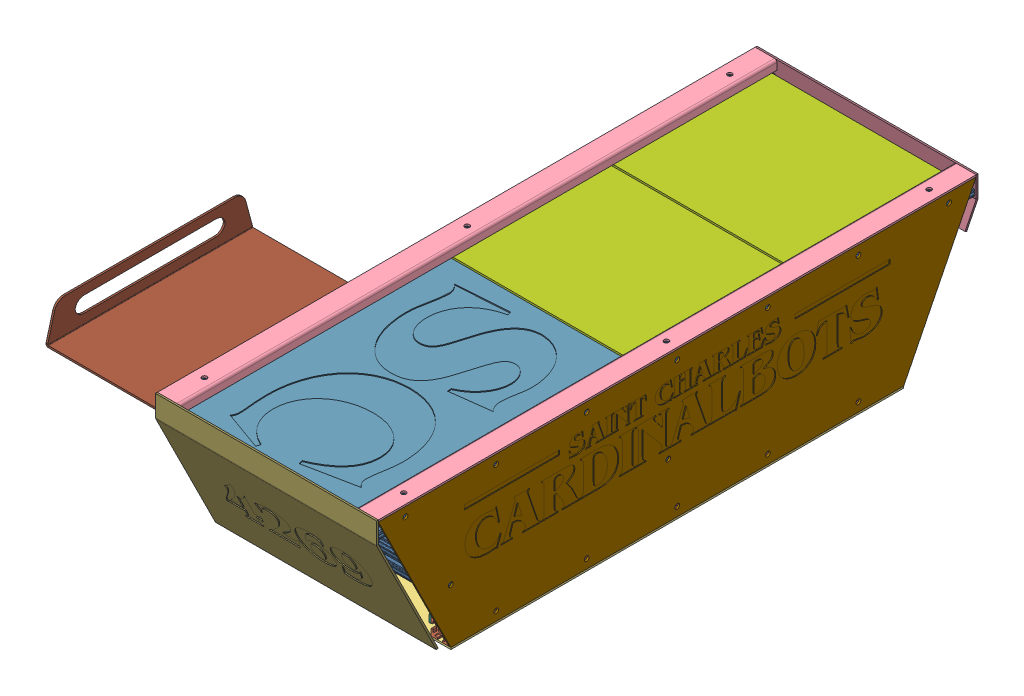
SolidWorks assembly Drive Station Assembly, configuration Default. Lengths in mm.
Overall size (576.52 208.28 843.28).
22 component instances, 14 part files, 56 mates.
Components (placement in the parent):
- Drive Station Side with T-Slot-1: Drive Station Side with T-Slot [Default] at (368.9985 440.9846 611.3533) size (25.4 203.2 838.2)
  - Modifiable T-Slot Bar (33 in)-1: Modifiable T-Slot Bar (33 in) [Default] at (22.4388 294.0274 200.7009) x (0 0 1) z (-1 0 0) size (838.2 25.4 25.4)
  - Modifiable T-Slot Bar (25 in)-1: Modifiable T-Slot Bar (25 in) [Default] at (-71.4513 116.2274 637.1834) x (0 0 -1) z (1 0 0) size (635 25.4 25.4)
- Drive station bottom plate-1: Drive station bottom plate [Default] at (484.1923 585.9717 1081.0955) x (0 0 1) z (-1 0 0) size (635 2.54 309.88)
- Drive Station Side with T-Slot-2: Drive Station Side with T-Slot [Default] at (599.3861 440.9846 1550.8376) x (-1 0 0) z (0 0 -1) size (25.4 203.2 838.2)
  - Modifiable T-Slot Bar (33 in)-1: Modifiable T-Slot Bar (33 in) [Default] at (22.4388 294.0274 200.7009) x (0 0 1) z (-1 0 0) size (838.2 25.4 25.4)
  - Modifiable T-Slot Bar (25 in)-1: Modifiable T-Slot Bar (25 in) [Default] at (-71.4513 116.2274 637.1834) x (0 0 -1) z (1 0 0) size (635 25.4 25.4)
- T-slot cover - 33-1: T-slot cover - 33 [Default] at (625.1623 791.7117 1081.0955) x (0 0 -1) z (1 0 0) size (838.2 12.7 30.48)
- T-slot cover - 33-2: T-slot cover - 33 [Default] at (343.2223 791.7117 1081.0955) x (0 0 1) z (-1 0 0) size (838.2 12.7 30.48)
- Electronics Plate-1: Electronics Plate [Default] at (483.8846 597.9732 1076.7796) x (0 0 -1) z (0 1 0) size (508 269.24 2.54)
- T-slot cover - 25-1: T-slot cover - 25 [Default] at (623.8923 613.9117 1081.0955) x (0 0 -1) z (1 0 0) size (635 12.7 27.94)
- T-slot cover - 25-2: T-slot cover - 25 [Default] at (344.4923 613.9117 1081.0955) x (0 0 1) z (-1 0 0) size (635 12.7 27.94)
- Joystick Plate-1: Joystick Plate [Default] at (485.4086 773.2332 1001.7205) x (0 0 1) z (0 -1 0) size (222.25 269.24 2.54)
- Joystick Plate-2: Joystick Plate [Default] at (483.8846 773.2332 776.9305) x (0 0 1) z (0 -1 0) size (222.25 269.24 2.54)
- Drive Station Side Plate Back-1: Drive Station Side Plate Back [Default] at (331.7923 789.1717 1500.1955) size (2.54 203.2 838.2)
- Drive Station Side Plate Front-1: Drive Station Side Plate Front [Default] at (639.1323 789.1717 1500.1955) size (2.54 203.2 838.2)
- Modifiable T-Slot Bar (12 in)-1: Modifiable T-Slot Bar (12 in) [Default] at (481.851 620.712 1351.6504) size (304.8 25.4 25.4)
- Modifiable T-Slot Bar (12 in)-2: Modifiable T-Slot Bar (12 in) [Default] at (481.851 709.1167 1052.3358) x (1 0 0) z (0 -1 0) size (304.8 25.4 25.4)
- Buttons Tray-1: Buttons Tray [Default] at (208.6612 661.4732 1246.1955) x (0 0 1) z (-1 0 0) size (287.02 50.8 289.56)
- Left Side Plate-1: Left Side Plate [Default] at (484.1923 773.9317 1502.7355) x (0 0 1) z (-1 0 0) size (86.34 198.59 309.88)
- Right Side Plate-1: Right Side Plate [Default] at (484.1923 773.9317 659.4555) x (0 0 -1) z (1 0 0) size (152.23 198.59 309.88)
- Laptop Plate-2: Laptop Plate [Default] at (485.4086 773.2332 1305.8855) x (0 0 -1) z (0 -1 0) size (381 269.24 2.54)
Mates (geometry in assembly coordinates):
- Coincident1: coincident anti-aligned: plane of Drive Station Side with T-Slot-1/Modifiable T-Slot Bar (25 in)-1 through (357.1923 585.9717 763.5955) normal (0 -1 0); plane of Drive station bottom plate-1 through (484.1923 585.9717 1081.0955) normal (0 1 0)
- Coincident2: coincident aligned: plane of Drive Station Side with T-Slot-1/Modifiable T-Slot Bar (25 in)-1 through (357.1923 585.9717 1398.5955) normal (0 0 1); plane of Drive station bottom plate-1 through (329.2523 583.4317 1398.5955) normal (0 0 1)
- Coincident3: coincident aligned: plane of ? through (329.2523 789.032 1500.1955) normal (-1 0 0); plane of Drive station bottom plate-1 through (329.2523 583.4317 763.5955) normal (-1 0 0)
- Parallel1: parallel aligned: plane of Drive station bottom plate-1 through (639.1323 583.4317 763.5955) normal (1 0 0); plane of ? through (639.1323 789.032 661.9955) normal (1 0 0)
- Coincident7: coincident anti-aligned: plane of Drive station bottom plate-1 through (484.1923 585.9717 1081.0955) normal (0 1 0); plane of Drive Station Side with T-Slot-2/Modifiable T-Slot Bar (25 in)-1 through (611.1923 585.9717 1398.5955) normal (0 -1 0)
- Coincident8: coincident aligned: plane of Drive station bottom plate-1 through (329.2523 583.4317 763.5955) normal (0 0 -1); plane of Drive Station Side with T-Slot-2/Modifiable T-Slot Bar (25 in)-1 through (611.1923 585.9717 763.5955) normal (0 0 -1)
- Coincident9: coincident aligned: plane of Drive station bottom plate-1 through (639.1323 583.4317 763.5955) normal (1 0 0); plane of ? through (639.1323 789.032 661.9955) normal (1 0 0)
- Coincident11: coincident anti-aligned: plane of Drive Station Side with T-Slot-2/Modifiable T-Slot Bar (33 in)-1 through (636.5923 789.1717 661.9955) normal (0 1 0); plane of T-slot cover - 33-1 through (625.1623 789.1717 1081.0955) normal (0 -1 0)
- Coincident12: coincident aligned: plane of ? through (639.1323 789.032 661.9955) normal (1 0 0); plane of T-slot cover - 33-1 through (639.1323 789.1717 1500.1955) normal (1 0 0)
- Coincident13: coincident aligned: plane of Drive Station Side with T-Slot-2/Modifiable T-Slot Bar (33 in)-1 through (636.5923 763.7717 1500.1955) normal (0 0 1); plane of T-slot cover - 33-1 through (639.1323 789.1717 1500.1955) normal (0 0 1)
- Coincident14: coincident anti-aligned: plane of Drive Station Side with T-Slot-1/Modifiable T-Slot Bar (33 in)-1 through (331.7923 789.1717 1500.1955) normal (0 1 0); plane of T-slot cover - 33-2 through (343.2223 789.1717 1081.0955) normal (0 -1 0)
- Coincident15: coincident aligned: plane of ? through (329.2523 789.032 1500.1955) normal (-1 0 0); plane of T-slot cover - 33-2 through (329.2523 789.1717 661.9955) normal (-1 0 0)
- Coincident16: coincident aligned: plane of Drive Station Side with T-Slot-1/Modifiable T-Slot Bar (33 in)-1 through (331.7923 763.7717 661.9955) normal (0 0 -1); plane of T-slot cover - 33-2 through (329.2523 789.1717 661.9955) normal (0 0 -1)
- Coincident19: coincident anti-aligned: plane of Drive Station Side with T-Slot-2/Modifiable T-Slot Bar (25 in)-1 through (611.1923 595.4332 1398.5955) normal (0 1 0); plane of Electronics Plate-1 through (483.8846 595.4332 1076.7796) normal (0 -1 0)
- Parallel2: parallel aligned: plane of Drive Station Side with T-Slot-1/Modifiable T-Slot Bar (25 in)-1 through (357.1923 585.9717 763.5955) normal (0 0 -1); plane of Electronics Plate-1 through (618.5046 595.4332 822.7796) normal (0 0 -1)
- Distance2: distance = 0.762 mm anti-aligned: plane of Electronics Plate-1 through (618.5046 595.4332 1330.7796) normal (1 0 0); plane of Drive Station Side with T-Slot-2/Modifiable T-Slot Bar (25 in)-1 through (619.2666 585.9717 1398.5955) normal (-1 0 0)
- Coincident22: coincident anti-aligned: plane of Drive Station Side with T-Slot-2/Modifiable T-Slot Bar (25 in)-1 through (611.1923 611.3717 1398.5955) normal (0 1 0); plane of T-slot cover - 25-1 through (623.8923 611.3717 1081.0955) normal (0 -1 0)
- Coincident23: coincident aligned: plane of Drive Station Side with T-Slot-2/Modifiable T-Slot Bar (25 in)-1 through (611.1923 585.9717 763.5955) normal (0 0 -1); plane of T-slot cover - 25-1 through (636.5923 611.3717 763.5955) normal (0 0 -1)
- Coincident24: coincident anti-aligned: plane of ? through (636.5923 789.032 661.9955) normal (-1 0 0); plane of T-slot cover - 25-1 through (636.5923 611.3717 1398.5955) normal (1 0 0)
- Coincident25: coincident anti-aligned: plane of Drive Station Side with T-Slot-1/Modifiable T-Slot Bar (25 in)-1 through (357.1923 611.3717 763.5955) normal (0 1 0); plane of T-slot cover - 25-2 through (344.4923 611.3717 1081.0955) normal (0 -1 0)
- Coincident26: coincident anti-aligned: plane of ? through (331.7923 789.032 1500.1955) normal (1 0 0); plane of T-slot cover - 25-2 through (331.7923 611.3717 763.5955) normal (-1 0 0)
- Coincident27: coincident: plane of Drive Station Side with T-Slot-1/Modifiable T-Slot Bar (25 in)-1 through (357.1923 585.9717 763.5955) normal (0 0 -1); line of T-slot cover - 25-2 through (356.4557 611.3717 763.5955) axis (-1 0 0)
- Coincident31: coincident anti-aligned: plane of Drive Station Side with T-Slot-2/Modifiable T-Slot Bar (33 in)-1 through (636.5923 773.2332 661.9955) normal (0 1 0); plane of Joystick Plate-1 through (485.4086 773.2332 1001.7205) normal (0 -1 0)
- Coincident32: coincident aligned: plane of Joystick Plate-1 through (485.4086 773.2332 1001.7205) normal (0 -1 0); plane of Joystick Plate-2 through (483.8846 773.2332 776.9305) normal (0 -1 0)
- Distance4: distance = 0.762 mm anti-aligned: plane of Joystick Plate-1 through (620.0286 775.7732 890.5955) normal (1 0 0); plane of Drive Station Side with T-Slot-2/Modifiable T-Slot Bar (33 in)-1 through (619.2666 763.7717 661.9955) normal (-1 0 0)
- Distance5: distance = 0.762 mm anti-aligned: plane of Drive Station Side with T-Slot-2/Modifiable T-Slot Bar (33 in)-1 through (619.2666 763.7717 661.9955) normal (-1 0 0); plane of Joystick Plate-2 through (618.5046 775.7732 665.8055) normal (1 0 0)
- Coincident35: coincident anti-aligned: plane of Drive Station Side with T-Slot-1/Modifiable T-Slot Bar (33 in)-1 through (331.7923 763.7717 1500.1955) normal (-1 0 0); plane of Drive Station Side Plate Back-1 through (331.7923 789.1717 1500.1955) normal (1 0 0)
- Coincident38: coincident anti-aligned: plane of T-slot cover - 33-2 through (343.2223 789.1717 1081.0955) normal (0 -1 0); plane of Drive Station Side Plate Back-1 through (329.2523 789.1717 1500.1955) normal (0 1 0)
- Coincident39: coincident anti-aligned: line of T-slot cover - 33-2 through (356.4557 789.1717 661.9955) axis (-1 0 0); line of Drive Station Side Plate Back-1 through (329.2523 789.1717 661.9955) axis (1 0 0)
- Coincident40: coincident anti-aligned: plane of T-slot cover - 25-2 through (331.7923 611.3717 763.5955) normal (-1 0 0); plane of Drive Station Side Plate Back-1 through (331.7923 789.1717 1500.1955) normal (1 0 0)
- Coincident42: coincident: line of Drive Station Side with T-Slot-2/Modifiable T-Slot Bar (25 in)-1 through (636.5923 605.2142 1398.5955) axis (0 1 0); plane of T-slot cover - 25-1 through (636.5923 611.3717 1398.5955) normal (1 0 0)
- Coincident44: coincident anti-aligned: plane of Drive Station Side with T-Slot-2/Modifiable T-Slot Bar (33 in)-1 through (611.1923 763.7717 661.9955) normal (-1 0 0); plane of T-slot cover - 33-1 through (611.1923 791.7117 1081.0955) normal (1 0 0)
- Coincident45: coincident anti-aligned: plane of Drive Station Side with T-Slot-2/Modifiable T-Slot Bar (33 in)-1 through (636.5923 763.7717 661.9955) normal (1 0 0); plane of Drive Station Side Plate Front-1 through (636.5923 789.1717 1500.1955) normal (-1 0 0)
- Coincident46: coincident anti-aligned: line of T-slot cover - 33-1 through (639.1323 789.1717 1500.1955) axis (0 0 -1); line of Drive Station Side Plate Front-1 through (639.1323 789.1717 661.9955) axis (0 0 1)
- Coincident47: coincident: plane of T-slot cover - 33-1 through (639.1323 789.1717 1500.1955) normal (0 0 1); line of Drive Station Side Plate Front-1 through (636.5923 789.1717 1500.1955) axis (1 0 0)
- Coincident48: coincident aligned: plane of Drive station bottom plate-1 through (639.1323 583.4317 763.5955) normal (1 0 0); plane of Drive Station Side Plate Front-1 through (639.1323 789.1717 1500.1955) normal (1 0 0)
- Coincident49: coincident aligned: plane of Drive station bottom plate-1 through (329.2523 583.4317 763.5955) normal (-1 0 0); plane of Drive Station Side Plate Back-1 through (329.2523 789.1717 1500.1955) normal (-1 0 0)
- Coincident50: coincident anti-aligned: plane of Drive Station Side Plate Back-1 through (331.7923 789.1717 1500.1955) normal (1 0 0); plane of Modifiable T-Slot Bar (12 in)-1 through (331.7923 649.4717 1411.2955) normal (-1 0 0)
- Concentric1: concentric anti-aligned: circle of Drive Station Side Plate Back-1; circle of Modifiable T-Slot Bar (12 in)-1
- Parallel5: parallel anti-aligned: plane of T-slot cover - 25-2 through (344.4923 613.9117 1081.0955) normal (0 1 0); plane of Modifiable T-Slot Bar (12 in)-1 through (636.5923 649.4717 1411.2955) normal (0 -1 0)
- Coincident52: coincident anti-aligned: plane of Drive Station Side Plate Back-1 through (331.7923 789.1717 1500.1955) normal (1 0 0); plane of Modifiable T-Slot Bar (12 in)-2 through (331.7923 649.4717 1081.0955) normal (-1 0 0)
- Concentric2: concentric anti-aligned: circle of Drive Station Side Plate Back-1; circle of Modifiable T-Slot Bar (12 in)-2
- Parallel6: parallel anti-aligned: plane of Electronics Plate-1 through (483.8846 597.9732 1076.7796) normal (0 1 0); plane of Modifiable T-Slot Bar (12 in)-2 through (636.5923 649.4717 1081.0955) normal (0 -1 0)
- Distance6: distance = 2.54 mm anti-aligned: plane of Buttons Tray-1 through (65.1512 658.9332 1102.6855) normal (0 0 -1); plane of Drive Station Side Plate Back-1 through (331.7923 659.6317 1100.1455) normal (0 0 1)
- Coincident55: coincident anti-aligned: plane of Modifiable T-Slot Bar (12 in)-2 through (636.5923 658.9332 1081.0955) normal (0 1 0); plane of Buttons Tray-1 through (208.6612 658.9332 1246.1955) normal (0 -1 0)
- Coincident56: coincident anti-aligned: plane of Drive Station Side with T-Slot-1/Modifiable T-Slot Bar (33 in)-1 through (331.7923 763.7717 1500.1955) normal (0 0 1); plane of Left Side Plate-1 through (484.1923 773.9317 1500.1955) normal (0 0 -1)
- Coincident57: coincident aligned: plane of T-slot cover - 33-2 through (343.2223 791.7117 1081.0955) normal (0 1 0); plane of Left Side Plate-1 through (329.2523 791.7117 1500.1955) normal (0 1 0)
- Coincident58: coincident aligned: plane of Drive Station Side Plate Back-1 through (329.2523 789.1717 1500.1955) normal (-1 0 0); plane of Left Side Plate-1 through (329.2523 756.1517 1500.1955) normal (-1 0 0)
- Coincident59: coincident anti-aligned: plane of Drive Station Side with T-Slot-2/Modifiable T-Slot Bar (33 in)-1 through (636.5923 763.7717 661.9955) normal (0 0 -1); plane of Right Side Plate-1 through (484.1923 773.9317 661.9955) normal (0 0 1)
- Coincident60: coincident aligned: plane of T-slot cover - 33-1 through (625.1623 791.7117 1081.0955) normal (0 1 0); plane of Right Side Plate-1 through (639.1323 791.7117 661.9955) normal (0 1 0)
- Coincident61: coincident aligned: plane of Drive Station Side Plate Front-1 through (639.1323 789.1717 1500.1955) normal (1 0 0); plane of Right Side Plate-1 through (639.1323 756.1517 661.9955) normal (1 0 0)
- Distance7: distance = 2.54 mm anti-aligned: plane of Joystick Plate-1 through (620.0286 775.7732 890.5955) normal (0 0 -1); plane of Joystick Plate-2 through (618.5046 775.7732 888.0555) normal (0 0 1)
- Coincident65: coincident anti-aligned: plane of Drive Station Side with T-Slot-2/Modifiable T-Slot Bar (33 in)-1 through (636.5923 773.2332 661.9955) normal (0 1 0); plane of Laptop Plate-2 through (485.4086 773.2332 1305.8855) normal (0 -1 0)
- Distance8: distance = 2.54 mm: line of Laptop Plate-2 through (350.7886 775.7732 1115.3855) axis (1 0 0); plane of Joystick Plate-1 through (620.0286 775.7732 1112.8455) normal (0 0 1)
- Coincident67: coincident aligned: plane of Joystick Plate-1 through (620.0286 775.7732 890.5955) normal (1 0 0); plane of Laptop Plate-2 through (620.0286 775.7732 1496.3855) normal (1 0 0)
- Distance9: distance = 3.81 mm anti-aligned: plane of Left Side Plate-1 through (484.1923 773.9317 1500.1955) normal (0 0 -1); plane of Laptop Plate-2 through (350.7886 775.7732 1496.3855) normal (0 0 1)
